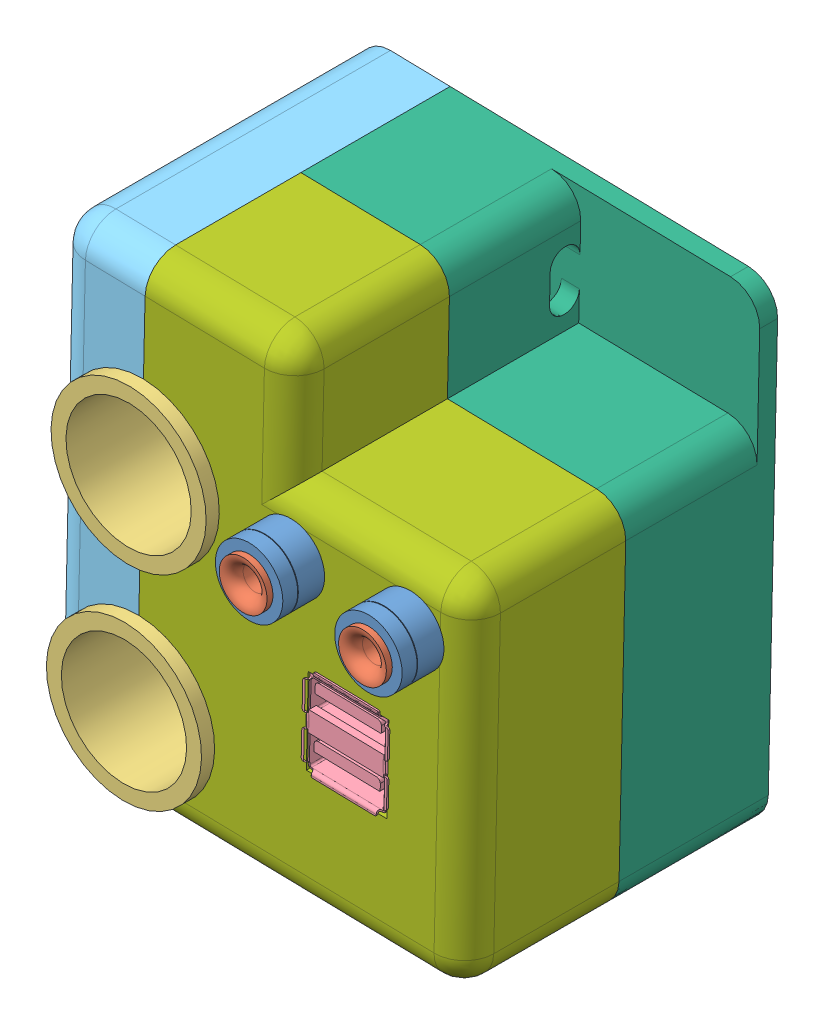
SolidWorks assembly Steckdose, configuration Standard. Lengths in mm.
Overall size (71.77 81.55 59).
12 component instances, 7 part files, 10 mates.
Components (placement in the parent):
- ST-351B V1 - BLACK-1: ST-351B V1 - BLACK [Default] at (-7.4592 2.2554 24.8608) size (11.3 11.3 22)
  - Insulator-1: Insulator [Default] at origin size (11.3 11.3 7)
  - Metal-1: Metal [Default] at (0 0 7.3) size (8 8 22)
- ST-351B V1 - BLACK-2: ST-351B V1 - BLACK [Default] at (12.5357 1.8079 24.8608) size (11.3 11.3 22)
  - Insulator-1: Insulator [Default] at origin size (11.3 11.3 7)
  - Metal-1: Metal [Default] at (0 0 7.3) size (8 8 22)
- Sockel_Zig-1: Sockel_Zig [Standard] at (-32.8412 -14.5308 27.3608) x (0.022377 0.99975 0) z (-0.99975 0.022377 0) size (61.95 48 27.25)
- usb_3_a-usb3_a-2p-1: usb_3_a-usb3_a-2p [Default] at (1.671 -27.7764 25.4608) x (0.99975 -0.022377 0) z (0 0 1) size (15.59 19.62 19.7)
- Steckdose-House-2: Steckdose-House [Standard] at (32.1871 -13.9931 -1.736) x (-0.022377 -0.99975 0) z (-0.99975 0.022377 0) size (80 51 70)
  - Steckdose-House-Left-1: Steckdose-House-Left [Standard] at (-45.5073 -24.1032 80) size (80 51 19.5)
  - Steckdose-House-Bottom-1: Steckdose-House-Bottom [Standard] at (-45.5073 -24.1032 80) size (80 25 55)
  - Steckdose-House-Top-1: Steckdose-House-Top [Standard] at (-45.5073 -24.1032 80) size (80 30.8 55)
Mates (geometry in assembly coordinates):
- Deckungsgleich1: coincident aligned: plane of ST-351B V1 - BLACK-1/Insulator-1 through (-7.4592 2.2554 25.1608) normal (0 0 -1); plane of ST-351B V1 - BLACK-2/Insulator-1 through (12.5357 1.8079 25.1608) normal (0 0 -1)
- Deckungsgleich2: coincident aligned: plane of ST-351B V1 - BLACK-1/Insulator-1 through (-7.4592 2.2554 25.1608) normal (0 0 -1); plane of Sockel_Zig-1 through (-32.453 2.8148 25.1608) normal (0 0 -1)
- Deckungsgleich3: coincident aligned: plane of ST-351B V1 - BLACK-1/Insulator-1 through (-7.4592 2.2554 25.1608) normal (0 0 -1); plane of usb_3_a-usb3_a-2p-1 through (10.0157 -12.4646 25.1608) normal (0 0 -1)
- Konzentrisch4: concentric aligned: cylinder of Sockel_Zig-1 through (-32.453 2.8148 -11.1392) axis (0 0 1) radius 11.05; cylinder of Steckdose-House-2/Steckdose-House-Top-1 through (-32.453 2.8148 22.1608) axis (0 0 1) radius 11.05
- Konzentrisch5: concentric aligned: cylinder of Sockel_Zig-1 through (-33.2295 -31.8765 -11.1392) axis (0 0 1) radius 11.05; cylinder of Steckdose-House-2/Steckdose-House-Left-1 through (-33.2295 -31.8765 22.1608) axis (0 0 1) radius 11.05
- Deckungsgleich14: coincident anti-aligned: plane of Sockel_Zig-1 through (-32.453 2.8148 25.1608) normal (0 0 -1); plane of Steckdose-House-2/Steckdose-House-Top-1 through (-46.7745 33.293 25.1608) normal (0 0 1)
- Deckungsgleich15: coincident anti-aligned: plane of usb_3_a-usb3_a-2p-1 through (-3.6459 -12.8337 4.8608) normal (0.022377 0.99975 0); plane of Steckdose-House-2/Steckdose-House-Top-1 through (8.9509 -13.1157 22.1608) normal (-0.022377 -0.99975 0)
- Deckungsgleich16: coincident anti-aligned: plane of usb_3_a-usb3_a-2p-1 through (-4.5591 -13.4134 4.8608) normal (-0.99975 0.022377 0); plane of Steckdose-House-2/Steckdose-House-Top-1 through (-4.5457 -12.8136 22.1608) normal (0.99975 -0.022377 0)
- Konzentrisch6: concentric aligned: cylinder of ST-351B V1 - BLACK-2/Metal-1 through (12.5357 1.8079 11.1608) axis (0 0 1) radius 3; cylinder of Steckdose-House-2/Steckdose-House-Top-1 through (12.5357 1.8079 22.1608) axis (0 0 1) radius 3
- Konzentrisch7: concentric aligned: cylinder of ST-351B V1 - BLACK-1/Metal-1 through (-7.4592 2.2554 11.1608) axis (0 0 1) radius 3; cylinder of Steckdose-House-2/Steckdose-House-Top-1 through (-7.4592 2.2554 22.1608) axis (0 0 1) radius 3
